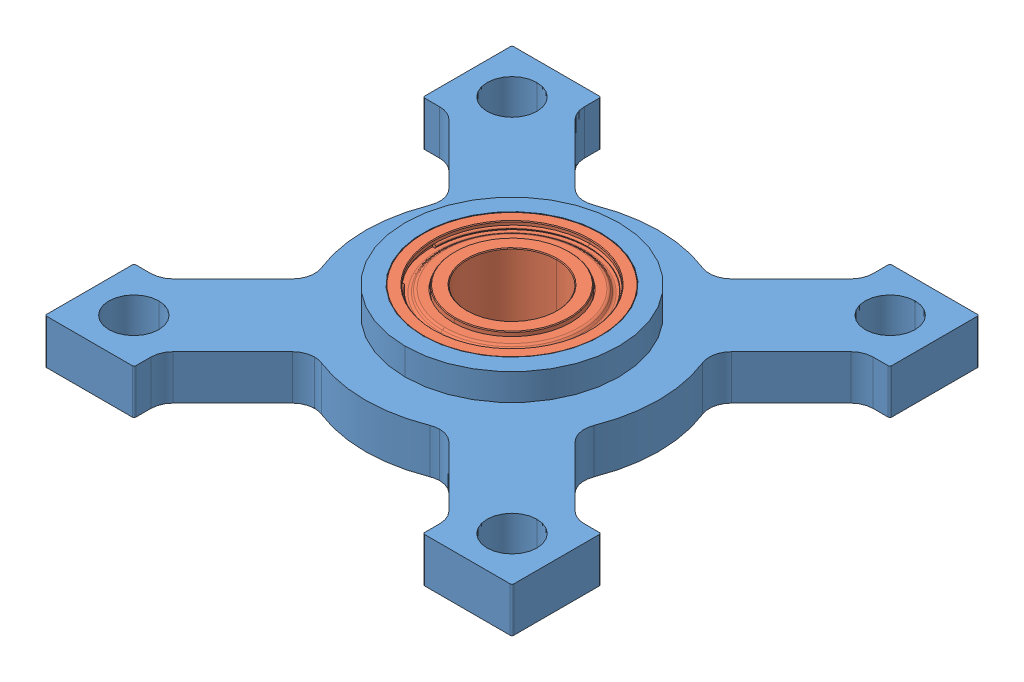
SolidWorks assembly 535110 assembly - Pillow.STEP, configuration Default. Lengths in mm.
Overall size (33.27 5.08 33.27).
2 component instances, 2 part files, 0 mates.
Components (placement in the parent):
- 535110.STEP-1: 535110.STEP [Default] at (6.6273 15.2478 28.3097) size (33.27 5.08 33.27)
- 535020.STEP-1: 535020.STEP [Default] at (6.6273 17.9338 28.3097) size (12.7 4.76 12.7)
